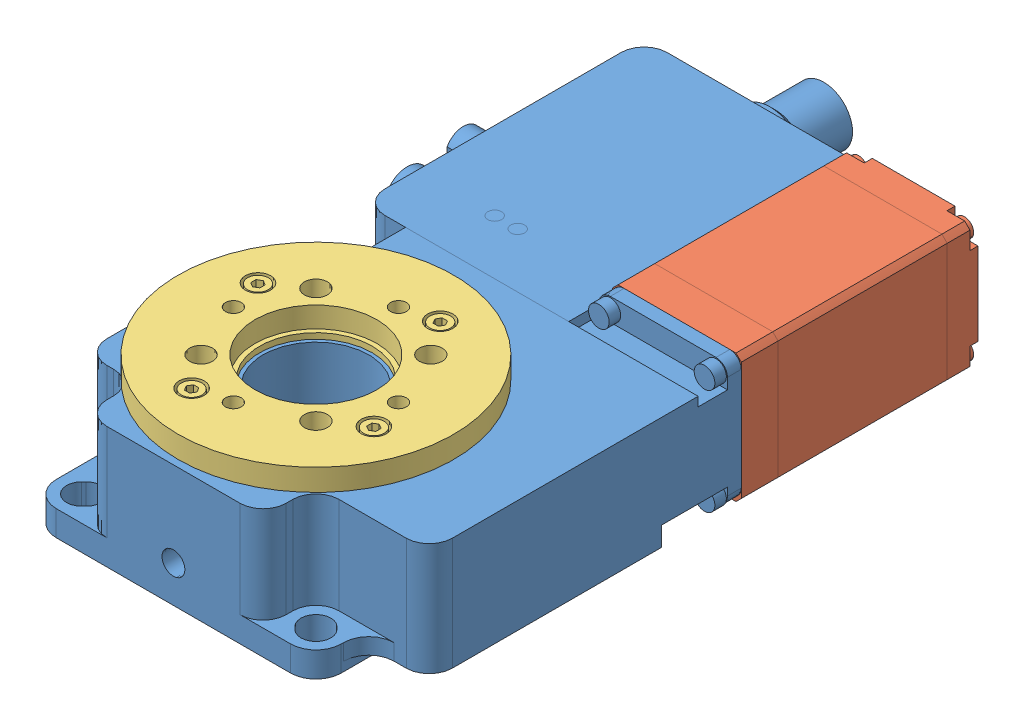
SolidWorks assembly RSW60, configuration X-RSW60x. Lengths in mm.
Overall size (82.66 31.75 146.4).
3 component instances, 3 part files, 9 mates.
Components (placement in the parent):
- RSW60_base^RSW60-1: RSW60_base^RSW60 [X-RSW60] x (0 0 1) z (-1 0 0) size (146.4 29.38 82.66) (virtual)
- NMS11_motor^RSW60-1: NMS11_motor^RSW60 [NMS11] at (30.16 15.38 -48.388) x (-1 0 0) z (0 0 1) (virtual)
- RSW60_top^RSW60-1: RSW60_top^RSW60 [RSW60] x (0 0 -1) z (1 0 0) (virtual)
Mates (geometry in assembly coordinates):
- Coincident1: coincident anti-aligned: plane of RSW60_base^RSW60-1 through (16.16 26.5 -48.388) normal (0 0 -1); plane of NMS11_motor^RSW60-1 through (30.16 15.38 -48.388) normal (0 0 1)
- Coincident3: coincident aligned: plane of RSW60_base^RSW60-1; plane of RSW60_top^RSW60-1
- Concentric2: concentric: cylinder of RSW60_base^RSW60-1 through (30.16 15.38 -46.388) axis (0 0 -1) radius 11; point of NMS11_motor^RSW60-1
- Parallel1: parallel anti-aligned: plane of NMS11_motor^RSW60-1; plane of assembly through (0 0 0) normal (0 1 0)
- Concentric3: concentric: cylinder of RSW60_base^RSW60-1 through (0 26.5 0) axis (0 -1 0) radius 11.5; point of RSW60_top^RSW60-1
- Coincident4: coincident: point of RSW60_base^RSW60-1; point of assembly
- Coincident6: coincident aligned: plane of RSW60_base^RSW60-1; plane of assembly through (0 0 0) normal (0 1 0)
- Coincident7: coincident anti-aligned: plane of RSW60_base^RSW60-1 through (0 0 0) normal (-1 0 0); plane of assembly through (0 0 0) normal (1 0 0)
- Home Position: coincident anti-aligned: plane of RSW60_top^RSW60-1 through (0 0 0) normal (1 0 0); plane of RSW60_base^RSW60-1 through (0 0 0) normal (-1 0 0)
